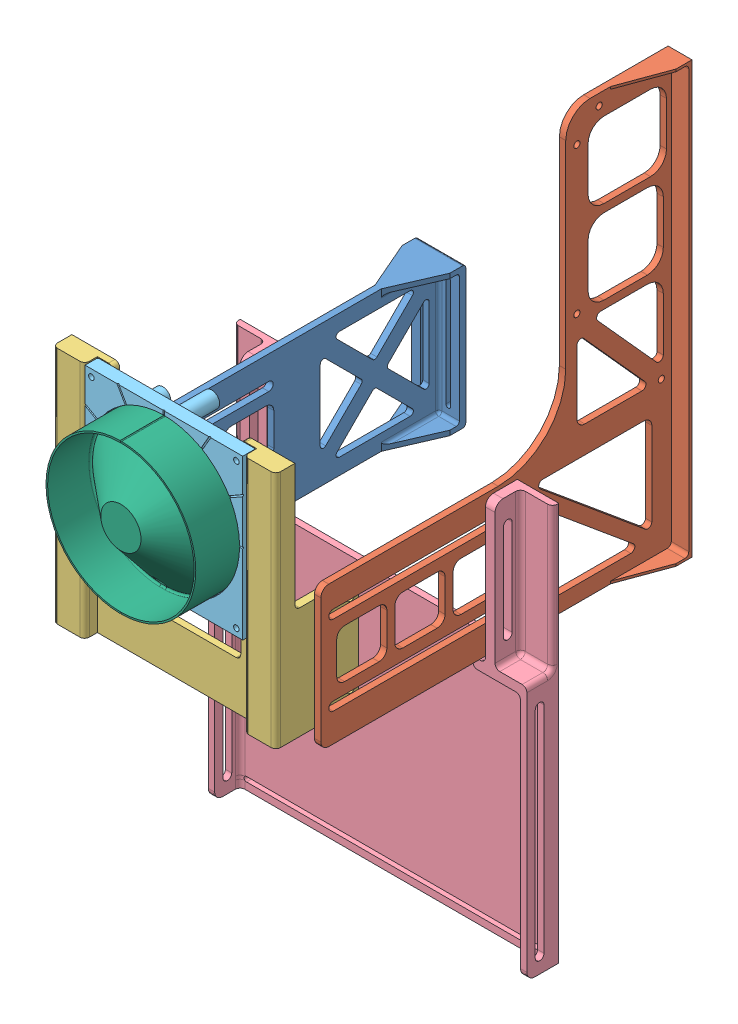
SolidWorks assembly Feeder assembly, configuration Default. Lengths in mm.
Overall size (200 434.25 273.25).
6 component instances, 6 part files, 17 mates.
Components (placement in the parent):
- Feeder rail support_Left-1: Feeder rail support_Left [Default] at (-96.1853 264.4096 163.9593) size (30 88.35 222)
- Feeder rail support_Right-1: Feeder rail support_Right [Default] at (60.8147 314.7618 163.9593) size (15 270.35 222)
- feeder rail 2.0-1: feeder rail 2.0 [Default] at (112.8147 197.5118 396.5468) x (0 1 0) z (1 0 0) size (150 52 140)
- Arduino Support-1: Arduino Support [Default] at (112.8147 73.0118 280.9445) x (-1 0 0) z (0 -1 0) size (200 20 250)
- Outer Cap 4.0-1: Outer Cap 4.0 [Default] at (112.5647 222.0118 400.5468) x (-1 0 0) z (0 1 0) size (99 30.03 100)
- Inner cap 3.0_with marking-1: Inner cap 3.0_with marking [Default] at (112.5647 222.0118 405.5468) x (1 0 0) z (0 -1 0) size (94 30 94.11)
Mates (geometry in assembly coordinates):
- Parallel1: parallel aligned: plane of Feeder rail support_Left-1 through (55.8147 200.2618 162.2968) normal (0 0 -1); plane of Feeder rail support_Right-1 through (197.8147 382.2618 162.2968) normal (0 0 -1)
- Parallel2: parallel aligned: plane of Feeder rail support_Left-1 through (38.8147 200.2618 384.2968) normal (-1 0 0); plane of Feeder rail support_Right-1 through (182.8147 242.6596 272.9445) normal (-1 0 0)
- Concentric1: concentric aligned: circle of Feeder rail support_Left-1; circle of feeder rail 2.0-1
- Concentric2: concentric aligned: circle of Feeder rail support_Left-1; circle of feeder rail 2.0-1
- Coincident3: coincident anti-aligned: plane of Feeder rail support_Left-1 through (42.8147 200.2618 384.2968) normal (1 0 0); plane of feeder rail 2.0-1 through (42.8147 122.5118 408.5468) normal (-1 0 0)
- Concentric3: concentric aligned: circle of Feeder rail support_Right-1; circle of feeder rail 2.0-1
- Concentric4: concentric anti-aligned: circle of Feeder rail support_Right-1; circle of feeder rail 2.0-1
- Coincident4: coincident anti-aligned: plane of Feeder rail support_Right-1 through (182.8147 242.6596 272.9445) normal (-1 0 0); plane of feeder rail 2.0-1 through (182.8147 122.5118 408.5468) normal (1 0 0)
- Perpendicular3: perpendicular: line of Feeder rail support_Right-1 through (186.8147 185.2618 376.5468) axis (0 0 -1); line of Arduino Support-1 through (186.8147 182.5118 275.6945) axis (0 -1 0)
- Perpendicular4: perpendicular: line of Feeder rail support_Left-1 through (38.8147 185.2618 376.5468) axis (0 0 -1); line of Arduino Support-1 through (38.8147 182.5118 270.1945) axis (0 -1 0)
- Concentric5: concentric anti-aligned: circle of Feeder rail support_Right-1; circle of Arduino Support-1
- Concentric6: concentric aligned: circle of Feeder rail support_Left-1; circle of Arduino Support-1
- Coincident12: coincident anti-aligned: plane of Feeder rail support_Right-1 through (186.8147 314.7618 163.9593) normal (1 0 0); plane of Arduino Support-1 through (186.8147 198.0118 280.9445) normal (-1 0 0)
- Coincident19: coincident anti-aligned: plane of feeder rail 2.0-1 through (112.8147 197.5118 400.5468) normal (0 0 1); plane of Outer Cap 4.0-1 through (112.5647 222.0118 400.5468) normal (0 0 -1)
- Parallel6: parallel anti-aligned: plane of feeder rail 2.0-1 through (162.8147 122.5118 400.5468) normal (-1 0 0); plane of Outer Cap 4.0-1 through (162.0647 172.0118 408.5468) normal (1 0 0)
- Concentric11: concentric anti-aligned: circle of Outer Cap 4.0-1; circle of Inner cap 3.0_with marking-1
- Coincident21: coincident anti-aligned: plane of Outer Cap 4.0-1 through (112.5647 222.0118 405.5468) normal (0 0 1); plane of Inner cap 3.0_with marking-1 through (112.5647 222.0118 405.5468) normal (0 0 -1)
